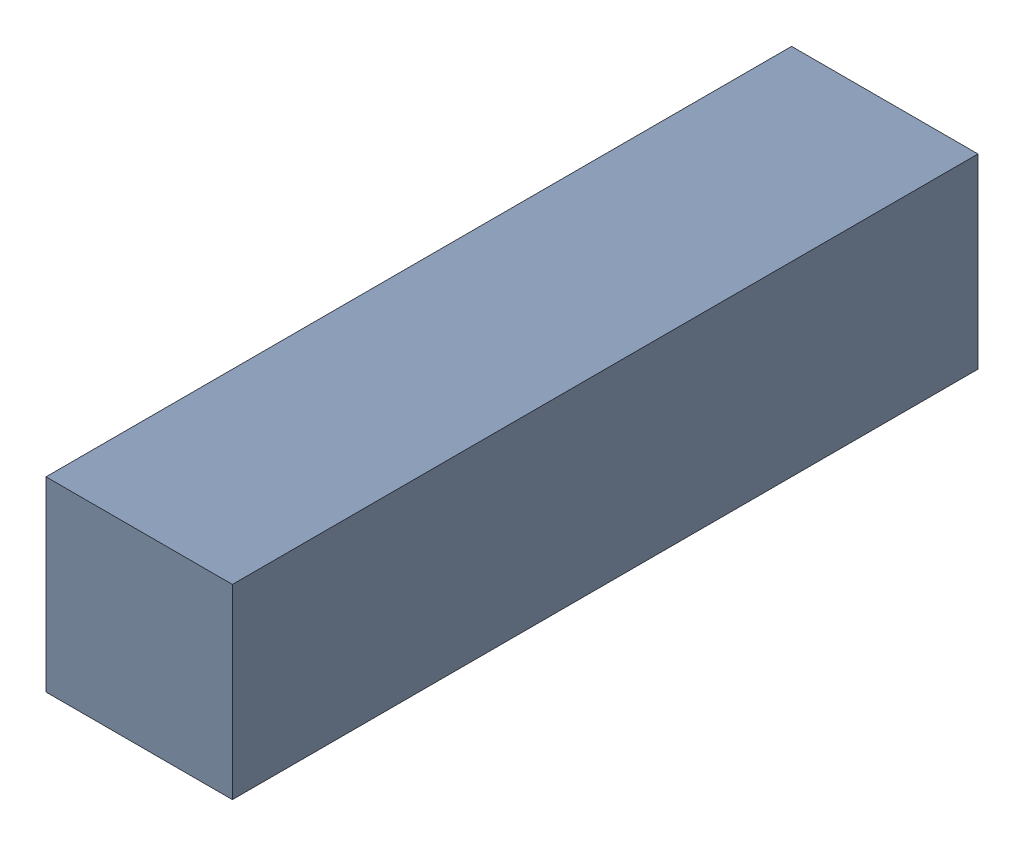
SolidWorks assembly CFD_Control_VolumeAndStructure_FullExtend, configuration Default. Lengths in mm.
Overall size (2540 2540 10160).
2 component instances, 2 part files, 6 mates.
Components (placement in the parent):
- CFD_Control_Volume_FullExtend-1: CFD_Control_Volume_FullExtend [Default] at (1425.0352 4676.4075 1994.3157) x (1 0 0) z (0 1 0) size (2540 10160 2540)
- CFD_Structure_FullExtend-1: CFD_Structure_FullExtend [Default] at (1425.0352 4688.2675 3264.3157) x (0 0 -1) z (1 0 0) (suppressed, hidden)
Mates (geometry in assembly coordinates):
- Parallel1: parallel anti-aligned: plane of CFD_Structure-1 through (2051.707 4305.7137 668.1383) normal (0 1 0); plane of CFD_Control_Volume-1 through (155.0352 3406.4075 -3085.6843) normal (0 -1 0)
- Parallel3: parallel anti-aligned: plane of CFD_Structure-1 through (1795.7289 4049.7356 668.1383) normal (-1 0 0); plane of CFD_Control_Volume-1 through (2695.0352 5946.4075 -3085.6843) normal (1 0 0)
- Distance2: distance = 387.35 mm aligned: plane of Final Test pls god-1 through (2307.6852 4049.7356 668.1383) normal (1 0 0); plane of CFD_Control_Volume-1 through (2695.0352 5946.4075 -3085.6843) normal (1 0 0)
- Distance3: distance = 387.35 mm aligned: plane of Final Test pls god-1 through (2051.707 3793.7575 668.1383) normal (0 -1 0); plane of CFD_Control_Volume-1 through (155.0352 3406.4075 -3085.6843) normal (0 -1 0)
- Distance4: distance = 3810 mm anti-aligned: plane of CFD_Structure_FullExtend-1 through (1425.0352 4688.2675 3264.3157) normal (0 0 -1); plane of CFD_Control_Volume-1 through (1425.0352 4676.4075 7074.3157) normal (0 0 1)
- Coincident2: coincident aligned: plane of CFD_Control_Volume-1 through (1425.0352 4676.4075 1994.3157) normal (1 0 0); plane of CFD_Structure_FullExtend-1 through (1425.0352 4688.2675 3264.3157) normal (1 0 0)
